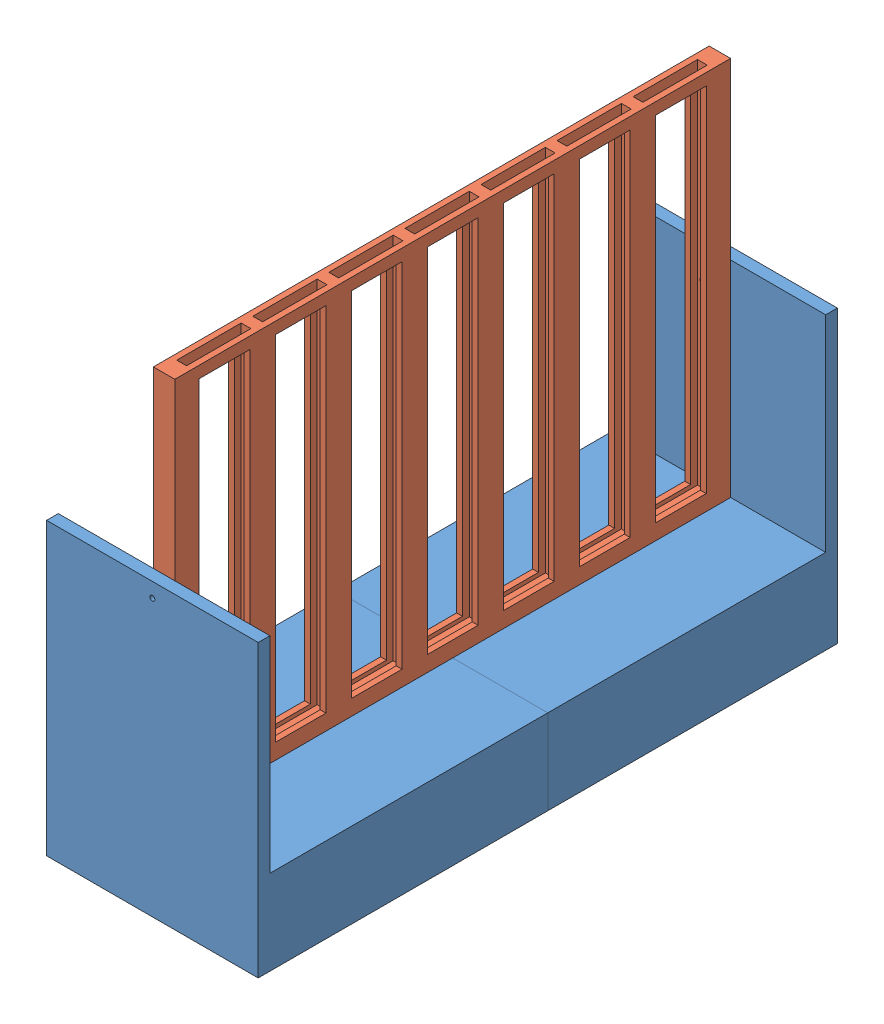
SolidWorks assembly Assem1, configuration Default. Lengths in mm.
Overall size (217 477 594).
3 component instances, 2 part files, 5 mates.
Components (placement in the parent):
- Connect 4 Simple Stands-3: Connect 4 Simple Stands [Default] at (0 149 -12) size (217 298 297)
- Connect 4 Simple Stands-4: Connect 4 Simple Stands [Default] at (0 149 -582) x (-1 0 0) z (0 0 -1) size (217 298 297)
- Connect 4 Simple Grid-1: Connect 4 Simple Grid [Default] at (-11 282 -297) x (0 0 -1) z (1 0 0) size (570 390 22)
Mates (geometry in assembly coordinates):
- Lock1: lock: unknown of ?
- Coincident11: coincident: plane of Connect 4 Simple Stands-3 through (0 149 -297) normal (0 0 -1); plane of Connect 4 Simple Stands-4 through (0 149 -297) normal (0 0 1)
- Coincident12: coincident: line of Connect 4 Simple Stands-3 through (108.5 87 -297) axis (0 0 1); line of Connect 4 Simple Stands-4 through (108.5 87 -297) axis (0 0 -1)
- Concentric1: concentric: cylinder of Connect 4 Simple Stands-4 through (0 283 -594) axis (0 0 1) radius 2.5; cylinder of Connect 4 Simple Grid-1 through (0 283 -11.999) axis (0 0 -1) radius 2.5
- Coincident13: coincident: plane of Connect 4 Simple Stands-4 through (0 149 -582) normal (0 0 1); plane of Connect 4 Simple Grid-1 through (11 87 -582) normal (0 0 -1)
